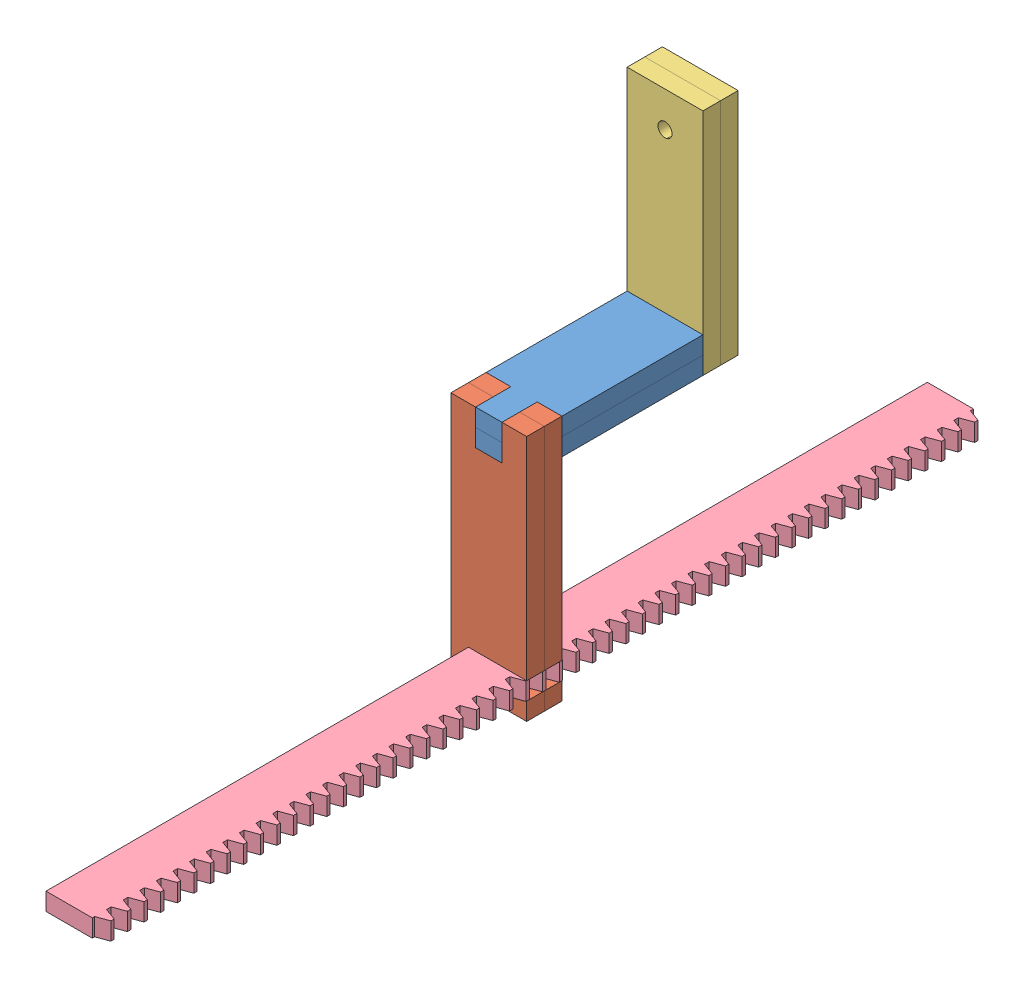
SolidWorks assembly Pulley Arm Assembly, configuration Default. Lengths in mm.
Overall size (21.5 125 250).
7 component instances, 4 part files, 17 mates.
Components (placement in the parent):
- Pulley Arm Platform-1: Pulley Arm Platform [Default] at (19.5289 31.0756 47.7284) size (21.5 5 60)
- Pulley Arm Platform-2: Pulley Arm Platform [Default] at (19.5289 36.0756 47.7284) size (21.5 5 60)
- Pulley Arm Base-1: Pulley Arm Base [Default] at (19.5289 6.0756 72.7284) x (1 0 0) z (0 -1 0) size (21.5 5 70)
- Pulley Arm Base-2: Pulley Arm Base [Default] at (19.5289 6.0756 67.7284) x (1 0 0) z (0 -1 0) size (21.5 5 70)
- Pulley Arm Top-1: Pulley Arm Top [Default] at (19.5289 63.5756 27.7284) x (-1 0 0) z (0 -1 0) size (21.5 5 65)
- Pulley Arm Top-2: Pulley Arm Top [Default] at (19.5289 63.5756 17.7284) x (1 0 0) z (0 -1 0) size (21.5 5 65)
- rack spur rectangular_am-1: rack spur rectangular_am [Metric - Rack-spur - rectangular 1.5M 20PA 5FW 15PH 250L---SAll] at (13.7789 -23.9244 197.572) x (0 0 -1) z (0 -1 0) size (250 16.5 5)
Mates (geometry in assembly coordinates):
- Coincident1: coincident aligned: plane of Pulley Arm Platform-1 through (30.2789 36.0756 27.7284) normal (1 0 0); plane of Pulley Arm Platform-2 through (30.2789 41.0756 27.7284) normal (1 0 0)
- Coincident2: coincident aligned: plane of Pulley Arm Platform-1 through (15.7789 36.0756 77.7284) normal (0 0 1); plane of Pulley Arm Platform-2 through (15.7789 41.0756 77.7284) normal (0 0 1)
- Coincident3: coincident anti-aligned: plane of Pulley Arm Platform-1 through (19.5289 36.0756 47.7284) normal (0 1 0); plane of Pulley Arm Platform-2 through (19.5289 36.0756 47.7284) normal (0 -1 0)
- Coincident4: coincident aligned: plane of Pulley Arm Platform-1 through (19.5289 31.0756 47.7284) normal (0 -1 0); plane of Pulley Arm Top-1 through (15.7789 31.0756 22.7284) normal (0 -1 0)
- Coincident7: coincident anti-aligned: plane of Pulley Arm Platform-2 through (23.2789 41.0756 17.7284) normal (1 0 0); plane of Pulley Arm Top-1 through (23.2789 41.0756 22.7284) normal (-1 0 0)
- Coincident8: coincident anti-aligned: plane of Pulley Arm Top-1 through (19.5289 63.5756 22.7284) normal (0 0 -1); plane of Pulley Arm Top-2 through (19.5289 63.5756 22.7284) normal (0 0 1)
- Coincident9: coincident aligned: plane of Pulley Arm Top-1 through (8.7789 96.0756 22.7284) normal (-1 0 0); plane of Pulley Arm Top-2 through (8.7789 96.0756 22.7284) normal (-1 0 0)
- Coincident10: coincident aligned: plane of Pulley Arm Top-1 through (30.2789 96.0756 22.7284) normal (0 1 0); plane of Pulley Arm Top-2 through (8.7789 96.0756 22.7284) normal (0 1 0)
- Coincident11: coincident anti-aligned: plane of Pulley Arm Platform-2 through (8.7789 41.0756 27.7284) normal (0 0 -1); plane of Pulley Arm Top-1 through (19.5289 63.5756 27.7284) normal (0 0 1)
- Coincident12: coincident anti-aligned: plane of Pulley Arm Platform-2 through (23.2789 41.0756 77.7284) normal (1 0 0); plane of Pulley Arm Base-2 through (23.2789 31.0756 72.7284) normal (-1 0 0)
- Coincident13: coincident anti-aligned: plane of Pulley Arm Platform-2 through (23.2789 41.0756 67.7284) normal (0 0 1); plane of Pulley Arm Base-2 through (19.5289 6.0756 67.7284) normal (0 0 -1)
- Coincident14: coincident aligned: plane of Pulley Arm Platform-2 through (19.5289 41.0756 47.7284) normal (0 1 0); plane of Pulley Arm Base-2 through (23.2789 41.0756 72.7284) normal (0 1 0)
- Coincident15: coincident aligned: plane of Pulley Arm Base-1 through (8.7789 41.0756 77.7284) normal (-1 0 0); plane of Pulley Arm Base-2 through (8.7789 41.0756 72.7284) normal (-1 0 0)
- Coincident16: coincident anti-aligned: plane of Pulley Arm Base-1 through (19.5289 6.0756 72.7284) normal (0 0 -1); plane of Pulley Arm Base-2 through (19.5289 6.0756 72.7284) normal (0 0 1)
- Coincident17: coincident aligned: plane of Pulley Arm Platform-2 through (19.5289 41.0756 47.7284) normal (0 1 0); plane of Pulley Arm Base-1 through (8.7789 41.0756 77.7284) normal (0 1 0)
- Coincident18: coincident anti-aligned: plane of Pulley Arm Base-1 through (13.7789 -23.9244 77.7284) normal (1 0 0); plane of rack spur rectangular_am-1 through (13.7789 -18.9244 197.572) normal (-1 0 0)
- Coincident19: coincident anti-aligned: plane of Pulley Arm Base-1 through (30.2789 -23.9244 77.7284) normal (0 1 0); plane of rack spur rectangular_am-1 through (30.2789 -23.9244 197.572) normal (0 -1 0)
